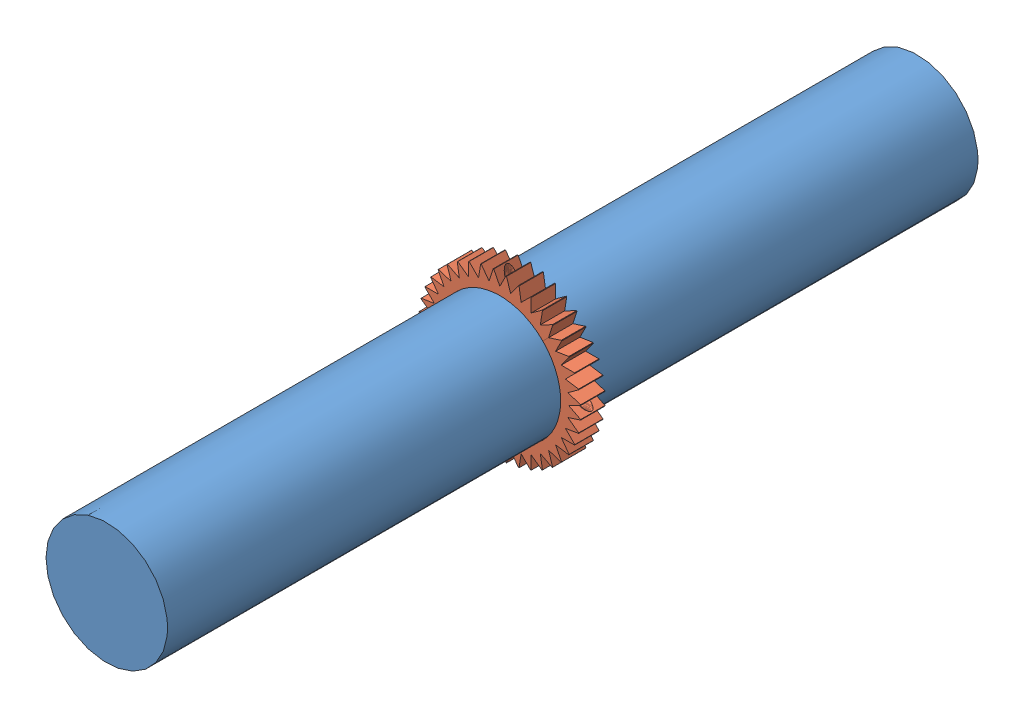
SolidWorks assembly 01-11-A-000-R00 Driveshaft Gear Assembly, configuration Default. Lengths in mm.
Overall size (141.02 141.02 500).
3 component instances, 2 part files, 9 mates.
Components (placement in the parent):
- 01-11-P-001-R00 Modified Driveshaft-2: 01-11-P-001-R00 Modified Driveshaft [Default] at origin size (75 75 500)
- 01-11-P-002-R00 Driveshaft Tooth Converter-1: 01-11-P-002-R00 Driveshaft Tooth Converter [Default] x (0.707107 0.707107 0) z (0 0 1) size (99.72 49.86 15)
- 01-11-P-002-R00 Driveshaft Tooth Converter-2: 01-11-P-002-R00 Driveshaft Tooth Converter [Default] x (-0.707107 -0.707107 0) z (0 0 1) size (99.72 49.86 15)
Mates (geometry in assembly coordinates):
- Coincident1: coincident: plane of 01-11-P-001-R00 Modified Driveshaft-2 through (0 0 0) normal (0 1 0); plane of assembly
- Coincident2: coincident: plane of 01-11-P-001-R00 Modified Driveshaft-2 through (0 0 0) normal (1 0 0); plane of assembly
- Coincident3: coincident aligned: plane of 01-11-P-001-R00 Modified Driveshaft-2 through (0 0 0) normal (0 0 1); plane of assembly
- Concentric1: concentric: cylinder of 01-11-P-001-R00 Modified Driveshaft-2 through (0 0 250) axis (0 0 -1) radius 37.5; cylinder of 01-11-P-002-R00 Driveshaft Tooth Converter-1 through (0 0 7.5) axis (0 0 -1) radius 37.5
- Concentric2: concentric: cylinder of 01-11-P-001-R00 Modified Driveshaft-2 through (0 0 250) axis (0 0 -1) radius 37.5; cylinder of 01-11-P-002-R00 Driveshaft Tooth Converter-2 through (0 0 7.5) axis (0 0 -1) radius 37.5
- Angle1: planar angle = 2.356194 rad: plane of 01-11-P-001-R00 Modified Driveshaft-2 through (0 0 0) normal (0 1 0); plane of 01-11-P-002-R00 Driveshaft Tooth Converter-2 through (0 0 0) normal (0.707107 -0.707107 0)
- Coincident5: coincident aligned: plane of 01-11-P-001-R00 Modified Driveshaft-2 through (0 0 0) normal (0 0 1); plane of 01-11-P-002-R00 Driveshaft Tooth Converter-2 through (0 0 0) normal (0 0 1)
- Angle2: planar angle = 0.785398 rad: plane of 01-11-P-002-R00 Driveshaft Tooth Converter-1 through (0 0 0) normal (-0.707107 0.707107 0); plane of 01-11-P-001-R00 Modified Driveshaft-2 through (0 0 0) normal (0 1 0)
- Coincident7: coincident aligned: plane of 01-11-P-001-R00 Modified Driveshaft-2 through (0 0 0) normal (0 0 1); plane of 01-11-P-002-R00 Driveshaft Tooth Converter-1 through (0 0 0) normal (0 0 1)
